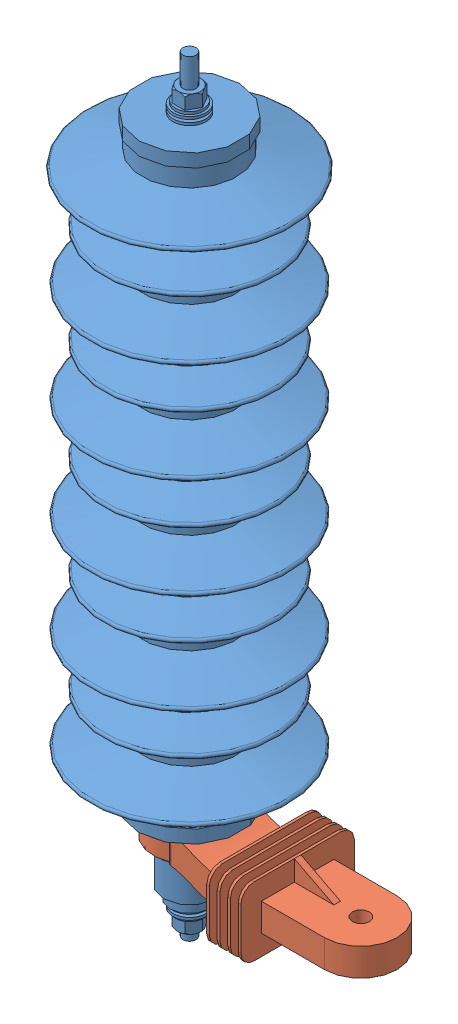
SolidWorks assembly YH10W-33L SAM bushing UNIT, configuration Default. Lengths in mm.
Overall size (234.25 581.11 153.5).
2 component instances, 2 part files, 2 mates.
Components (placement in the parent):
- YH10W-33L SAM bushing-1: YH10W-33L SAM bushing [Default] at (174.0876 30.2664 457.259) size (153.5 581.11 153.5)
- YH10W-XXL SAM bushing HOLDER-1: YH10W-XXL SAM bushing HOLDER [Default] at (304.0876 86.0768 457.259) size (185 52 86)
Mates (geometry in assembly coordinates):
- Parallel1: parallel: YH10W-33L SAM bushing-1, YH10W-XXL SAM bushing HOLDER-1
- Concentric1: concentric: YH10W-33L SAM bushing-1, YH10W-XXL SAM bushing HOLDER-1
